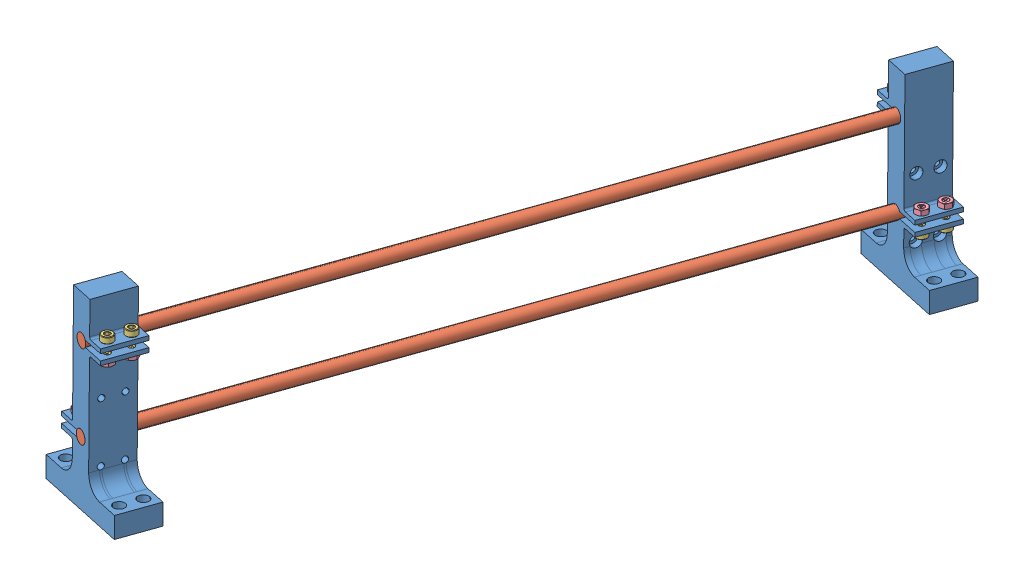
SolidWorks assembly main_rail, configuration Default. Lengths in mm.
Overall size (149.98 111.44 361.78).
20 component instances, 4 part files, 39 mates.
Components (placement in the parent):
- side_rail-1: side_rail [Default] at (-136.746 357.9789 913.8043) x (0.271115 -0.050502 -0.961221) z (0.960657 0.076747 0.266924) size (20 90 50)
- side_rail-2: side_rail [Default] at (-39.5457 342.9411 613.2615) x (-0.271115 0.050502 0.961221) z (-0.960657 -0.076747 -0.266924) size (20 90 50)
- aluminum_rod-3: aluminum_rod [Default] at (-43.5048 401.2168 588.2761) x (-0.943985 0.18122 -0.275775) z (-0.271115 0.050502 0.961221) size (6.35 6.35 356)
- aluminum_rod-4: aluminum_rod [Default] at (-41.0932 361.386 591.0491) x (0.209719 0.977731 0.007782) z (-0.271115 0.050502 0.961221) size (6.35 6.35 356)
- 91292A112_18-8 Stainless Steel Socket Head Screw-2: 91292A112_18-8 Stainless Steel Socket Head Screw [91292A112] at (-54.1957 396.2209 590.725) x (-0.403527 -0.087836 -0.910742) z (0.060291 -0.995771 0.069323) size (5.5 5.5 11.2)
- 91828A211_18-8 Stainless Steel Hex Nut-2: 91828A211_18-8 Stainless Steel Hex Nut [91828A211] at (-54.1836 396.0217 590.7388) x (-0.818744 -0.009607 0.574078) z (0.060291 -0.995771 0.069323) size (5.5 6.35 2.78)
- 91292A112_18-8 Stainless Steel Socket Head Screw-3: 91292A112_18-8 Stainless Steel Socket Head Screw [91292A112] at (-35.8247 367.392 607.8247) x (-0.204301 0.055669 0.977324) z (-0.060291 0.995771 -0.069323) size (5.5 5.5 11.2)
- 91292A112_18-8 Stainless Steel Socket Head Screw-4: 91292A112_18-8 Stainless Steel Socket Head Screw [91292A112] at (-33.1135 366.8869 598.2124) x (-0.319332 -0.085041 -0.943819) z (-0.060291 0.995771 -0.069323) size (5.5 5.5 11.2)
- 91292A112_18-8 Stainless Steel Socket Head Screw-5: 91292A112_18-8 Stainless Steel Socket Head Screw [91292A112] at (-128.7884 415.2296 928.646) x (0.148895 -0.0597 -0.987049) z (0.060291 -0.995771 0.069323) size (5.5 5.5 11.2)
- 91292A112_18-8 Stainless Steel Socket Head Screw-6: 91292A112_18-8 Stainless Steel Socket Head Screw [91292A112] at (-143.4213 382.3208 915.8443) x (0.150989 -0.059552 -0.98674) z (-0.060291 0.995771 -0.069323) size (5.5 5.5 11.2)
- 91292A112_18-8 Stainless Steel Socket Head Screw-7: 91292A112_18-8 Stainless Steel Socket Head Screw [91292A112] at (-146.1325 382.8258 925.4565) x (0.856528 0.015948 -0.515854) z (-0.060291 0.995771 -0.069323) size (5.5 5.5 11.2)
- 91292A112_18-8 Stainless Steel Socket Head Screw-8: 91292A112_18-8 Stainless Steel Socket Head Screw [91292A112] at (-126.0772 414.7246 919.0338) x (0.139222 -0.060382 -0.988419) z (0.060291 -0.995771 0.069323) size (5.5 5.5 11.2)
- 91292A112_18-8 Stainless Steel Socket Head Screw-9: 91292A112_18-8 Stainless Steel Socket Head Screw [91292A112] at (-56.9068 396.7259 600.3372) x (0.673632 -0.01066 -0.73899) z (0.060291 -0.995771 0.069323) size (5.5 5.5 11.2)
- 91828A211_18-8 Stainless Steel Hex Nut-3: 91828A211_18-8 Stainless Steel Hex Nut [91828A211] at (-56.8948 396.5268 600.351) x (0.250899 0.082337 0.964505) z (-0.060291 0.995771 -0.069323) size (5.5 6.35 2.78)
- 91828A211_18-8 Stainless Steel Hex Nut-4: 91828A211_18-8 Stainless Steel Hex Nut [91828A211] at (-128.7763 415.0305 928.6598) x (-0.403444 -0.087833 -0.910779) z (0.060291 -0.995771 0.069323) size (5.5 6.35 2.78)
- 91828A211_18-8 Stainless Steel Hex Nut-5: 91828A211_18-8 Stainless Steel Hex Nut [91828A211] at (-35.8367 367.5911 607.8108) x (0.742939 -0.001616 -0.669357) z (0.060291 -0.995771 0.069323) size (5.5 6.35 2.78)
- 91828A211_18-8 Stainless Steel Hex Nut-6: 91828A211_18-8 Stainless Steel Hex Nut [91828A211] at (-33.1256 367.0861 598.1986) x (-0.810782 -0.008344 0.585288) z (-0.060291 0.995771 -0.069323) size (5.5 6.35 2.78)
- 91828A211_18-8 Stainless Steel Hex Nut-7: 91828A211_18-8 Stainless Steel Hex Nut [91828A211] at (-126.0651 414.5255 919.0476) x (0.064634 -0.065409 -0.995763) z (0.060291 -0.995771 0.069323) size (5.5 6.35 2.78)
- 91828A211_18-8 Stainless Steel Hex Nut-8: 91828A211_18-8 Stainless Steel Hex Nut [91828A211] at (-143.4334 382.5199 915.8304) x (-0.279772 0.049808 0.958774) z (-0.060291 0.995771 -0.069323) size (5.5 6.35 2.78)
- 91828A211_18-8 Stainless Steel Hex Nut-9: 91828A211_18-8 Stainless Steel Hex Nut [91828A211] at (-146.1445 383.025 925.4426) x (-0.413307 -0.08812 -0.906318) z (0.060291 -0.995771 0.069323) size (5.5 6.35 2.78)
Mates (geometry in assembly coordinates):
- Coincident2: coincident aligned: plane of side_rail-1 through (-130.0414 438.5615 911.4615) normal (-0.060291 0.995771 -0.069323); plane of side_rail-2 through (-55.8969 421.6818 604.5126) normal (-0.060291 0.995771 -0.069323)
- Coincident5: coincident aligned: plane of side_rail-1 through (-136.746 357.9789 913.8043) normal (-0.960657 -0.076747 -0.266924); plane of side_rail-2 through (-51.0736 342.0201 610.0584) normal (-0.960657 -0.076747 -0.266924)
- Concentric2: concentric anti-aligned: cylinder of side_rail-2 through (-43.5048 401.2168 588.2761) axis (-0.271115 0.050502 0.961221) radius 3.175; cylinder of aluminum_rod-3 through (-140.0218 419.1957 930.4709) axis (0.271115 -0.050502 -0.961221) radius 3.175
- Concentric3: concentric anti-aligned: cylinder of side_rail-2 through (-41.0932 361.386 591.0491) axis (-0.271115 0.050502 0.961221) radius 3.175; cylinder of aluminum_rod-4 through (-137.6102 379.3648 933.2438) axis (0.271115 -0.050502 -0.961221) radius 3.175
- Concentric7: concentric anti-aligned: cylinder of side_rail-2 through (-54.0002 392.992 590.9498) axis (-0.060291 0.995771 -0.069323) radius 1.5; cylinder of 91292A112_18-8 Stainless Steel Socket Head Screw-2 through (-54.8589 407.1744 589.9624) axis (0.060291 -0.995771 0.069323) radius 2.75
- Coincident11: coincident anti-aligned: plane of side_rail-2 through (-46.5978 403.7047 576.2141) normal (-0.060291 0.995771 -0.069323); plane of 91292A112_18-8 Stainless Steel Socket Head Screw-2 through (-54.678 404.1871 590.1704) normal (0.060291 -0.995771 0.069323)
- Concentric8: concentric anti-aligned: cylinder of 91292A112_18-8 Stainless Steel Socket Head Screw-2 through (-54.8589 407.1744 589.9624) axis (0.060291 -0.995771 0.069323) radius 2.75; circle of 91828A211_18-8 Stainless Steel Hex Nut-2
- Coincident12: coincident anti-aligned: plane of side_rail-2 through (-46.1758 396.7343 576.6993) normal (0.060291 -0.995771 0.069323); plane of 91828A211_18-8 Stainless Steel Hex Nut-2 through (-52.911 397.098 587.7816) normal (-0.060291 0.995771 -0.069323)
- Concentric9: concentric anti-aligned: cylinder of side_rail-2 through (-56.7113 393.497 600.562) axis (-0.060291 0.995771 -0.069323) radius 1.5; cylinder of 91292A112_18-8 Stainless Steel Socket Head Screw-9 through (-57.57 407.6794 599.5746) axis (0.060291 -0.995771 0.069323) radius 2.75
- Coincident13: coincident anti-aligned: plane of side_rail-2 through (-46.5978 403.7047 576.2141) normal (-0.060291 0.995771 -0.069323); plane of 91292A112_18-8 Stainless Steel Socket Head Screw-9 through (-57.3891 404.6921 599.7826) normal (0.060291 -0.995771 0.069323)
- Concentric10: concentric aligned: cylinder of side_rail-2 through (-32.3754 354.6961 599.0611) axis (-0.060291 0.995771 -0.069323) radius 1.5; cylinder of 91292A112_18-8 Stainless Steel Socket Head Screw-4 through (-32.4503 355.9335 598.975) axis (-0.060291 0.995771 -0.069323) radius 2.75
- Coincident14: coincident anti-aligned: plane of side_rail-2 through (-24.551 358.4384 584.8107) normal (0.060291 -0.995771 0.069323); plane of 91292A112_18-8 Stainless Steel Socket Head Screw-4 through (-32.6312 358.9208 598.767) normal (-0.060291 0.995771 -0.069323)
- Concentric11: concentric aligned: cylinder of side_rail-2 through (-35.0865 355.2011 608.6734) axis (-0.060291 0.995771 -0.069323) radius 1.5; cylinder of 91292A112_18-8 Stainless Steel Socket Head Screw-3 through (-35.1615 356.4385 608.5872) axis (-0.060291 0.995771 -0.069323) radius 2.75
- Coincident15: coincident anti-aligned: plane of side_rail-2 through (-24.551 358.4384 584.8107) normal (0.060291 -0.995771 0.069323); plane of 91292A112_18-8 Stainless Steel Socket Head Screw-3 through (-35.3423 359.4258 608.3792) normal (-0.060291 0.995771 -0.069323)
- Concentric12: concentric anti-aligned: cylinder of side_rail-1 through (-128.5928 412.0007 928.8708) axis (-0.060291 0.995771 -0.069323) radius 1.5; cylinder of 91292A112_18-8 Stainless Steel Socket Head Screw-5 through (-129.4516 426.1831 927.8834) axis (0.060291 -0.995771 0.069323) radius 2.75
- Coincident16: coincident anti-aligned: plane of side_rail-1 through (-137.3509 423.6782 942.0477) normal (-0.060291 0.995771 -0.069323); plane of 91292A112_18-8 Stainless Steel Socket Head Screw-5 through (-129.2707 423.1958 928.0914) normal (0.060291 -0.995771 0.069323)
- Concentric13: concentric anti-aligned: cylinder of side_rail-1 through (-125.8817 411.4957 919.2585) axis (-0.060291 0.995771 -0.069323) radius 1.5; cylinder of 91292A112_18-8 Stainless Steel Socket Head Screw-8 through (-126.7404 425.6781 918.2712) axis (0.060291 -0.995771 0.069323) radius 2.75
- Coincident17: coincident anti-aligned: plane of side_rail-1 through (-137.3509 423.6782 942.0477) normal (-0.060291 0.995771 -0.069323); plane of 91292A112_18-8 Stainless Steel Socket Head Screw-8 through (-126.5595 422.6908 918.4792) normal (0.060291 -0.995771 0.069323)
- Concentric14: concentric aligned: cylinder of side_rail-1 through (-145.3944 370.6349 926.3052) axis (-0.060291 0.995771 -0.069323) radius 1.5; cylinder of 91292A112_18-8 Stainless Steel Socket Head Screw-7 through (-145.4693 371.8723 926.219) axis (-0.060291 0.995771 -0.069323) radius 2.75
- Coincident18: coincident anti-aligned: plane of side_rail-1 through (-153.7303 375.342 939.9674) normal (0.060291 -0.995771 0.069323); plane of 91292A112_18-8 Stainless Steel Socket Head Screw-7 through (-145.6501 374.8596 926.0111) normal (-0.060291 0.995771 -0.069323)
- Concentric15: concentric aligned: cylinder of side_rail-1 through (-142.6832 370.1299 916.693) axis (-0.060291 0.995771 -0.069323) radius 1.5; cylinder of 91292A112_18-8 Stainless Steel Socket Head Screw-6 through (-142.7581 371.3673 916.6068) axis (-0.060291 0.995771 -0.069323) radius 2.75
- Coincident19: coincident anti-aligned: plane of side_rail-1 through (-153.7303 375.342 939.9674) normal (0.060291 -0.995771 0.069323); plane of 91292A112_18-8 Stainless Steel Socket Head Screw-6 through (-142.939 374.3546 916.3989) normal (-0.060291 0.995771 -0.069323)
- Concentric16: concentric anti-aligned: cylinder of 91292A112_18-8 Stainless Steel Socket Head Screw-9 through (-57.57 407.6794 599.5746) axis (0.060291 -0.995771 0.069323) radius 2.75; circle of 91828A211_18-8 Stainless Steel Hex Nut-3
- Coincident20: coincident anti-aligned: plane of side_rail-2 through (-46.1758 396.7343 576.6993) normal (0.060291 -0.995771 0.069323); plane of 91828A211_18-8 Stainless Steel Hex Nut-3 through (-56.1231 397.56 597.2109) normal (-0.060291 0.995771 -0.069323)
- Concentric17: concentric aligned: cylinder of 91292A112_18-8 Stainless Steel Socket Head Screw-7 through (-145.4693 371.8723 926.219) axis (-0.060291 0.995771 -0.069323) radius 2.75; circle of 91828A211_18-8 Stainless Steel Hex Nut-9
- Coincident22: coincident anti-aligned: plane of side_rail-1 through (-154.1524 382.3124 939.4822) normal (-0.060291 0.995771 -0.069323); plane of 91828A211_18-8 Stainless Steel Hex Nut-9 through (-143.493 382.1136 927.3563) normal (0.060291 -0.995771 0.069323)
- Concentric18: concentric aligned: cylinder of 91292A112_18-8 Stainless Steel Socket Head Screw-6 through (-142.7581 371.3673 916.6068) axis (-0.060291 0.995771 -0.069323) radius 2.75; circle of 91828A211_18-8 Stainless Steel Hex Nut-8
- Coincident23: coincident anti-aligned: plane of side_rail-1 through (-154.1524 382.3124 939.4822) normal (-0.060291 0.995771 -0.069323); plane of 91828A211_18-8 Stainless Steel Hex Nut-8 through (-141.0704 381.3106 913.7145) normal (0.060291 -0.995771 0.069323)
- Concentric19: concentric anti-aligned: cylinder of 91292A112_18-8 Stainless Steel Socket Head Screw-3 through (-35.1615 356.4385 608.5872) axis (-0.060291 0.995771 -0.069323) radius 2.75; circle of 91828A211_18-8 Stainless Steel Hex Nut-5
- Coincident24: coincident anti-aligned: plane of side_rail-2 through (-24.973 365.4088 584.3254) normal (-0.060291 0.995771 -0.069323); plane of 91828A211_18-8 Stainless Steel Hex Nut-5 through (-36.749 366.5465 610.9091) normal (0.060291 -0.995771 0.069323)
- Concentric20: concentric aligned: cylinder of 91292A112_18-8 Stainless Steel Socket Head Screw-4 through (-32.4503 355.9335 598.975) axis (-0.060291 0.995771 -0.069323) radius 2.75; circle of 91828A211_18-8 Stainless Steel Hex Nut-6
- Coincident25: coincident anti-aligned: plane of side_rail-2 through (-24.973 365.4088 584.3254) normal (-0.060291 0.995771 -0.069323); plane of 91828A211_18-8 Stainless Steel Hex Nut-6 through (-29.8991 366.0594 597.9549) normal (0.060291 -0.995771 0.069323)
- Concentric21: concentric anti-aligned: cylinder of 91292A112_18-8 Stainless Steel Socket Head Screw-8 through (-126.7404 425.6781 918.2712) axis (0.060291 -0.995771 0.069323) radius 2.75; circle of 91828A211_18-8 Stainless Steel Hex Nut-7
- Coincident26: coincident anti-aligned: plane of side_rail-1 through (-136.9288 416.7078 942.533) normal (0.060291 -0.995771 0.069323); plane of 91828A211_18-8 Stainless Steel Hex Nut-7 through (-124.7337 416.0027 921.7987) normal (-0.060291 0.995771 -0.069323)
- Concentric22: concentric anti-aligned: cylinder of 91292A112_18-8 Stainless Steel Socket Head Screw-5 through (-129.4516 426.1831 927.8834) axis (0.060291 -0.995771 0.069323) radius 2.75; circle of 91828A211_18-8 Stainless Steel Hex Nut-4
- Coincident27: coincident anti-aligned: plane of side_rail-1 through (-136.9288 416.7078 942.533) normal (0.060291 -0.995771 0.069323); plane of 91828A211_18-8 Stainless Steel Hex Nut-4 through (-126.2896 416.5097 930.435) normal (-0.060291 0.995771 -0.069323)
- Coincident28: coincident aligned: plane of side_rail-1 through (-130.6404 359.9099 936.2318) normal (-0.271115 0.050502 0.961221); plane of aluminum_rod-3 through (-140.0218 419.1957 930.4709) normal (-0.271115 0.050502 0.961221)
- Coincident29: coincident aligned: plane of side_rail-2 through (-45.6513 341.0101 590.834) normal (0.271115 -0.050502 -0.961221); plane of aluminum_rod-3 through (-43.5048 401.2168 588.2761) normal (0.271115 -0.050502 -0.961221)
- Coincident30: coincident aligned: plane of side_rail-1 through (-130.6404 359.9099 936.2318) normal (-0.271115 0.050502 0.961221); plane of aluminum_rod-4 through (-137.6102 379.3648 933.2438) normal (-0.271115 0.050502 0.961221)
